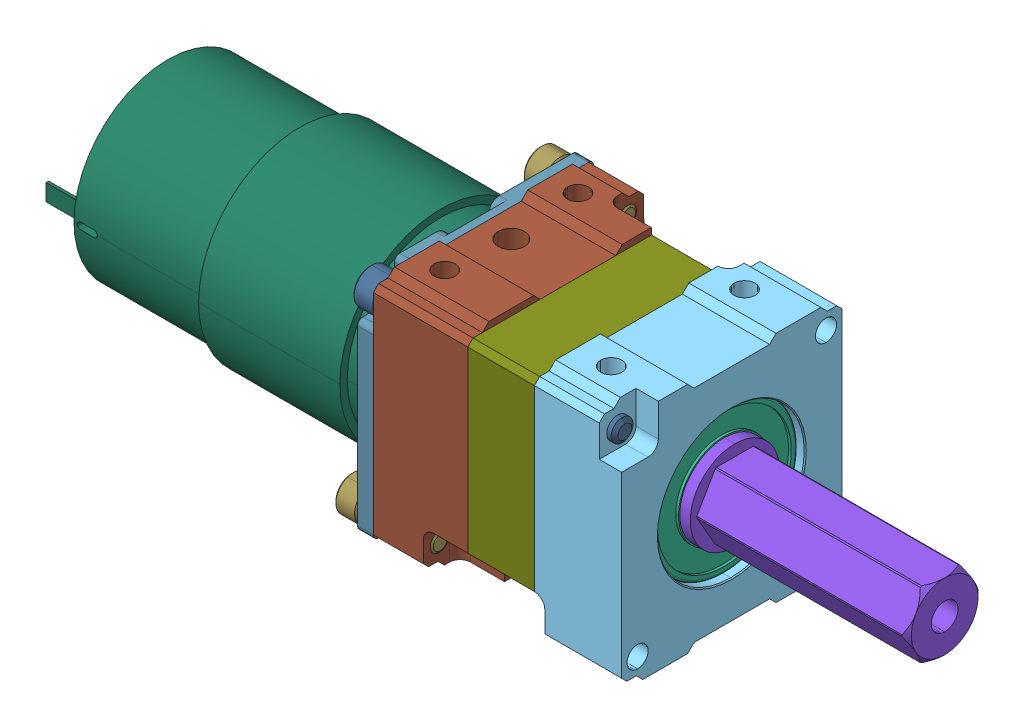
SolidWorks assembly VersaPlanetary v2 Single Stage 10_1 with RS 550 .step, configuration Default. Lengths in mm.
Overall size (155.67 51.55 52.65).
29 component instances, 19 part files, 0 mates.
Components (placement in the parent):
- 217-2820 Rev1_Public.step-1: 217-2820 Rev1_Public.step [Default] at (-4.6546 22.225 0) x (0 -0.456494 0.889726) z (-1 0 0) size (39.22 38.88 17.4)
  - 217-2625-100.step-1: 217-2625-100.step [Default] at origin size (39.22 38.88 12.7)
    - 217-2625-008 Rev1.step-1: 217-2625-008 Rev1.step [Default] at origin size (34.7 34.7 4.7)
    - 217-2625-010 Rev1.step-1: 217-2625-010 Rev1.step [Default] at (0 10.193 3.65) x (0.999813 0.019336 0) z (0 0 1) size (4 4 12)
    - 217-2625-010 Rev1.step-2: 217-2625-010 Rev1.step [Default] at (8.691 -5.3258 3.65) size (4 4 12)
    - 217-2625-010 Rev1.step-3: 217-2625-010 Rev1.step [Default] at (-8.691 -5.3258 3.65) size (4 4 12)
    - 217-2625-005 Rev1_Planet_Revolving_Follower01.step-1: 217-2625-005 Rev1_Planet_Revolving_Follower01.step [Default] at (8.691 -5.3258 6.35) x (0.932816 0.360354 0) z (0 0 1) size (16.89 16.89 8)
    - 217-2625-005 Rev1_Planet_Revolving_Follower01.step-2: 217-2625-005 Rev1_Planet_Revolving_Follower01.step [Default] at (-8.691 -5.3258 6.35) x (-0.932788 -0.360426 0) z (0 0 1) size (16.89 16.89 8)
    - 217-2625-005 Rev1_Planet_Revolving_Follower01.step-3: 217-2625-005 Rev1_Planet_Revolving_Follower01.step [Default] at (0 10.193 6.35) x (0.893583 0.448898 0) z (0 0 1) size (16.89 16.89 8)
  - 217-2625-007 Rev1_Public.step-1: 217-2625-007 Rev1_Public.step [Default] at (0 0 6.7) x (0.992772 0.120019 0) z (0 0 1) size (15.27 15.27 12.7)
- 217-2625-026 Rev1.step-1: 217-2625-026 Rev1.step [Default] at (-6.5 22.225 0) x (0 -1 0) z (-1 0 0) size (44.45 42 18.12)
- 217-2742-001 Rev4.step-1: 217-2742-001 Rev4.step [Default] at (0.2002 22.225 0) x (1 0 0) z (0 -0.092627 0.995701) size (7 28 28)
- 217-2742-001 Rev4.step-2: 217-2742-001 Rev4.step [Default] at (8.2002 22.225 0) size (7 28 28)
- 217-2625-017 Rev1_9714K61.step-1: 217-2625-017 Rev1_9714K61.step [Default] at (7.42 22.3002 -0.342) x (0 0.56703 0.823697) z (0 -0.823697 0.56703) size (28.51 4.98 27.43)
- 217-2625-003 Rev1.step-1: 217-2625-003 Rev1.step [Default] at (7.4478 22.225 0) x (0 -1 0) z (1 0 0) size (17 17 64.11)
- 217-2625-018 Rev1_98541A410.step-1: 217-2625-018 Rev1_98541A410.step [Default] at (-0.7046 22.225 0) x (1 0 0) z (0 -0.017452 0.999848) size (1 19.6 17.4)
- 832-1750-Ring-Gear-Screw_SSA0832-0500ZC.step-1: 832-1750-Ring-Gear-Screw_SSA0832-0500ZC.step [Default] at (-30.7 4.725 -17.5) x (0 0.997447 0.071411) z (0 -0.071411 0.997447) size (6.73 48.51 6.73)
- 832-1750-Ring-Gear-Screw_SSA0832-0500ZC.step-2: 832-1750-Ring-Gear-Screw_SSA0832-0500ZC.step [Default] at (-30.7 39.725 17.5) x (0 0.005929 0.999982) z (0 -0.999982 0.005929) size (6.73 48.51 6.73)
- 217-2625-025 Rev1.step-1: 217-2625-025 Rev1.step [Default] at (-23.2 22.225 0) x (0 -1 0) z (-1 0 0) size (44.45 42 18)
- 217-4649-002 Rev1_SSA0832-0500ZC.step-1: 217-4649-002 Rev1_SSA0832-0500ZC.step [Default] at (-33.7 4.2645 17.9605) x (0 0.33842 -0.940995) z (0 0.940995 0.33842) size (6.73 16.76 6.73)
- 217-4649-002 Rev1_SSA0832-0500ZC.step-2: 217-4649-002 Rev1_SSA0832-0500ZC.step [Default] at (-33.7 40.1855 -17.9605) x (0 -0.308932 -0.951084) z (0 0.951084 -0.308932) size (6.73 16.76 6.73)
- 217-4649-005 Rev1_SSA0003-008BA.step-1: 217-4649-005 Rev1_SSA0003-008BA.step [Default] at (-30.7 22.225 -12.5) x (0 -0.5 0.866025) z (0 0.866025 0.5) size (5.5 11 5.5)
- 217-4649-005 Rev1_SSA0003-008BA.step-2: 217-4649-005 Rev1_SSA0003-008BA.step [Default] at (-30.7 22.225 12.5) x (0 -0.5 -0.866025) z (0 -0.866025 0.5) size (5.5 11 5.5)
- 217-2822-001 Rev4.step-1: 217-2822-001 Rev4.step [Default] at (-32.2 22.225 0) x (0 1 0) z (-1 0 0) size (42 42 4.8)
- BaneBots RS550.step-1: BaneBots RS550.step [Default] at (-83.738 22.225 0) x (0 0 1) z (1 0 0) size (38.61 38.57 77.9)
- 217-2816-001 Rev1.step-1: 217-2816-001 Rev1.step [Default] at (-6.35 22.225 0) x (0 -1 0) z (1 0 0) size (42 42 14.51)
- 217-4649-001 Rev1.step-1: 217-4649-001 Rev1.step [Default] at (-20.046 22.225 0) x (0 -1 0) z (1 0 0) size (18 18 13)
- 217-4649-007 Rev1_94105A824.step-1: 217-4649-007 Rev1_94105A824.step [Default] at (-25.521 22.225 -6.7835) x (-0.996104 -0.088191 0) z (0 0 -1) size (4.83 4.83 4.77)
- 217-2625-012 Rev1.step-1: 217-2625-012 Rev1.step [Default] at (-21.0318 22.225 0) x (0 0 1) z (-1 0 0) size (8.01 7.94 7.5)
